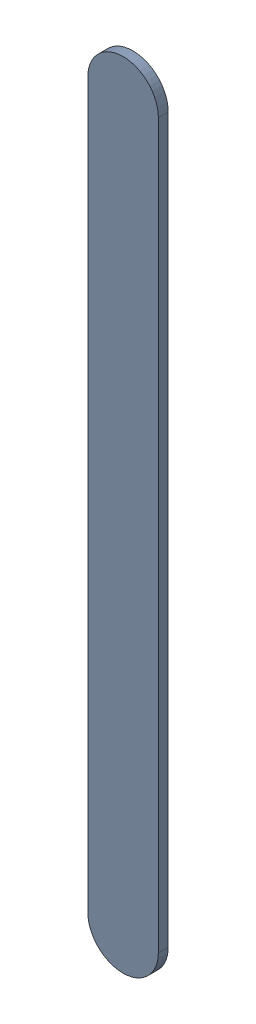
SolidWorks assembly Track (22.2mm,53.3mm)(22.2mm,55.903mm) on Top Layer, configuration Predeterminado. Lengths in mm.
Overall size (0.25 2.86 0.04).
2 component instances, 1 part files, 0 mates.
Components (placement in the parent):
- Track (22.2mm,53.3mm)(22.2mm,55.903mm) on Top Layer-1-1: Track (22.2mm,53.3mm)(22.2mm,55.903mm) on Top Layer-1 [Predeterminado] at (-68.317 -44.187 -0.0457) size (0.25 2.86 0.04)
  - Track (22.2mm,53.3mm)(22.2mm,55.903mm) on Top Layer-Part-1-1: Track (22.2mm,53.3mm)(22.2mm,55.903mm) on Top Layer-Part-1 [Predeterminado] at origin size (0.25 2.86 0.04)
